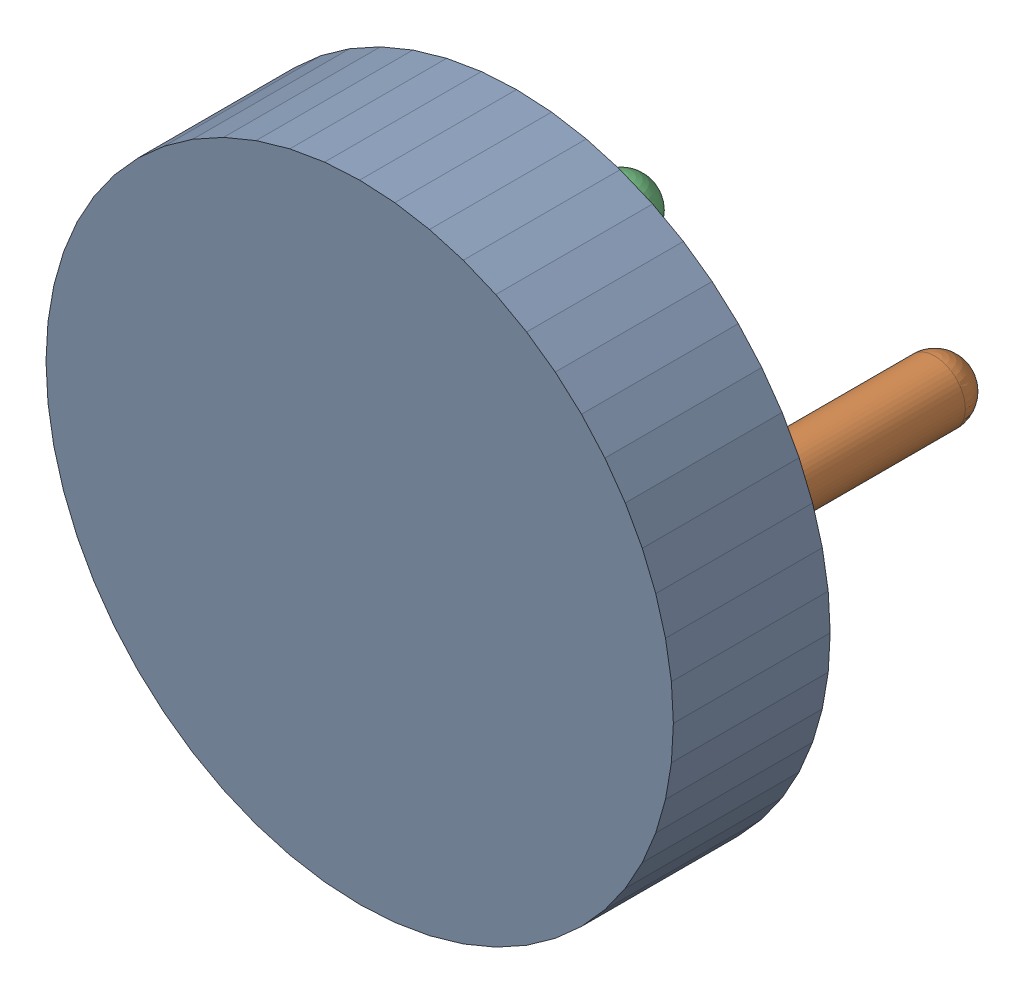
SolidWorks assembly Open CASCADE STEP translator 6.8 1.24.1, configuration Défaut. Lengths in mm.
Overall size (12 12 8.59).
3 component instances, 3 part files, 0 mates.
Components (placement in the parent):
- Body_1_11-1: Body_1_11 [Défaut] at origin size (12 12 3)
- Pin_1_8-1: Pin_1_8 [Défaut] x (0 -1 0) z (0 0 1) size (1.17 1.17 7.67)
- Pin_2_8-1: Pin_2_8 [Défaut] at (-6 -6 0) x (0 -1 0) z (0 0 1) size (1.17 1.17 7.67)
